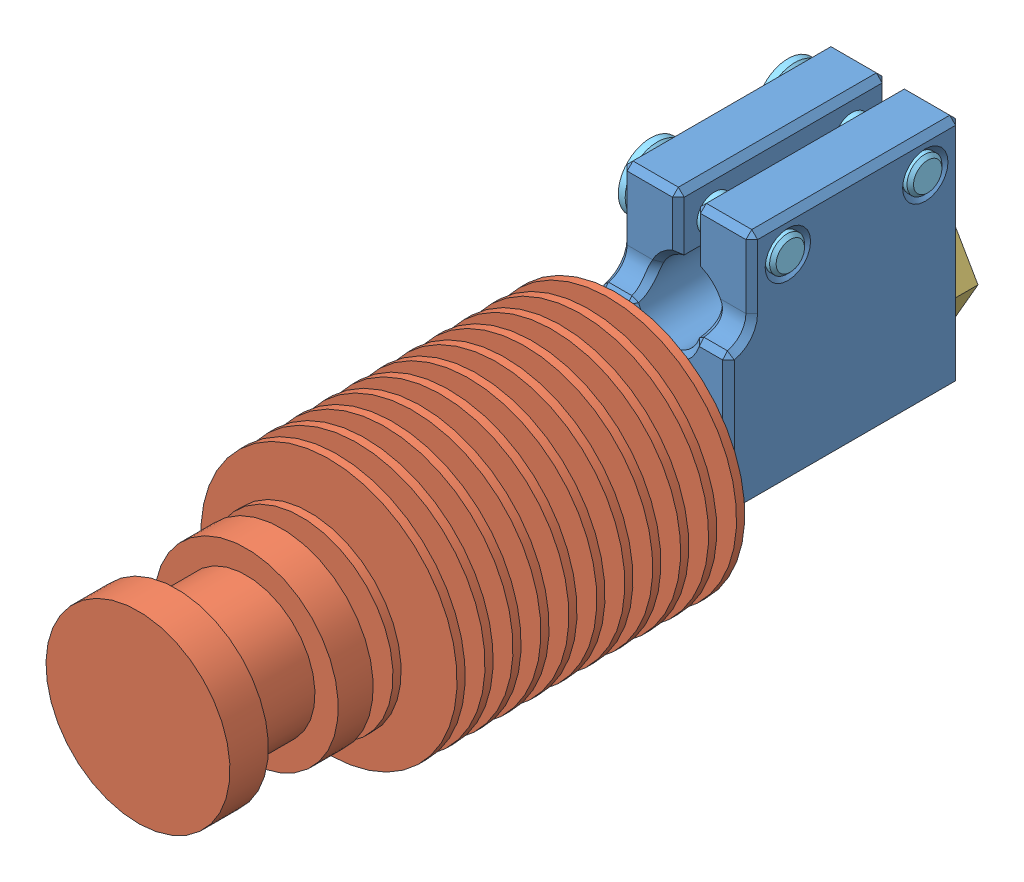
SolidWorks assembly Hotend Volcano J-head V6, configuration Valor predeterminado. Lengths in mm.
Overall size (26.65 29.04 70.3).
6 component instances, 5 part files, 19 mates.
Components (placement in the parent):
- Bloco Aquecedor-1: Bloco Aquecedor [Valor predeterminado] at origin size (11.2 20 20)
- Dissipador-1: Dissipador [Valor predeterminado] at (0.7469 3.7969 -4) x (0 0 -1) z (0.240623 -0.970619 0) size (41.1 22 22)
- Bico 0.4mm-1: Bico 0.4mm [Valor predeterminado] x (-1 0 0) z (0 0 -1) size (7.85 6.8 5.2)
- Tubo conector-1: Tubo conector [Valor predeterminado] at (0.7469 3.7969 24) x (-0.240623 0.970619 0) z (0 0 -1) size (6.8 6.8 4)
- socket countersunk head screw_iso-1: socket countersunk head screw_iso [ISO 10642 - M3 x 12 - 12N] at (-0.59 17.1 14.9) size (12 5.54 5.54)
- socket countersunk head screw_iso-2: socket countersunk head screw_iso [ISO 10642 - M3 x 12 - 12N] at (-0.59 17.1 3.1) x (1 0 0) z (0 0.924225 0.381849) size (12 5.54 5.54)
Mates (geometry in assembly coordinates):
- Coincidente1: coordinate: point of bloco aquecedor-1
- Concêntrico1: concentric aligned: cylinder of bloco aquecedor-1 through (5.6 5 20) axis (0 0 -1) radius 2.9; cylinder of Peça1^Hotend Volcano J-head V6-1 through (5.6 5 24) axis (0 0 -1) radius 11
- Distância1: distance = 4 mm anti-aligned: plane of bloco aquecedor-1 through (5.6 12.55 20) normal (0 0 1); plane of Peça1^Hotend Volcano J-head V6-1 through (5.6 5 24) normal (0 0 -1)
- No local2: in place: plane of Bloco Aquecedor-1 through (5.6 12.55 0) normal (0 0 -1); plane of Bico 0.4mm-1 through (0 0 0) normal (0 0 -1); moOrthogonalPlaneRef_w of Bloco Aquecedor-1 through (5.6 12.55 0) normal (0 0 -1); plane of Bico 0.4mm-1 through (0 0 0) normal (0 1 0); plane of Bloco Aquecedor-1 through (5.6 12.55 0) normal (0 0 -1); plane of Bico 0.4mm-1 through (0 0 0) normal (-1 0 0); plane of Bloco Aquecedor-1 through (5.6 12.55 0) normal (0 0 -1); unknown of Bico 0.4mm-1
- Coincidente5: coincident aligned: plane of ?; plane of ?
- Coincidente6: coincident aligned: moOrthogonalPlaneRef_w of bloco aquecedor-1 through (0 0 0) normal (0 1 0); plane of Peça2^Hotend Volcano J-head V6-1 through (0 0 0) normal (0 1 0)
- Coincidente7: coincident anti-aligned: moOrthogonalPlaneRef_w of bloco aquecedor-1 through (0 0 0) normal (1 0 0); plane of Peça2^Hotend Volcano J-head V6-1 through (0 0 0) normal (-1 0 0)
- No local3: in place: plane of Dissipador-1 through (5.6 5 24) normal (0 0 -1); plane of ? through (0 0 24) normal (0 0 -1); plane of Dissipador-1 through (5.6 5 24) normal (0 0 -1); plane of ? through (0 0 24) normal (0 1 0); plane of Dissipador-1 through (5.6 5 24) normal (0 0 -1); plane of ? through (0 0 24) normal (-1 0 0); plane of Dissipador-1 through (5.6 5 24) normal (0 0 -1); unknown of Tubo conector-1
- Coincidente8: coincident aligned: plane of ?; plane of ?
- Coincidente9: coincident aligned: moOrthogonalPlaneRef_w of Peça1^Hotend Volcano J-head V6-1 through (0.7469 3.7969 24) normal (0.970619 0.240623 0); plane of Peça3^Hotend Volcano J-head V6-1 through (0.7469 3.7969 24) normal (0.970619 0.240623 0)
- Coincidente10: coincident anti-aligned: moOrthogonalPlaneRef_w of Peça1^Hotend Volcano J-head V6-1 through (0.7469 3.7969 24) normal (0.240623 -0.970619 0); plane of Peça3^Hotend Volcano J-head V6-1 through (0.7469 3.7969 24) normal (-0.240623 0.970619 0)
- No local4: in place: plane of Dissipador-1 through (16.2768 7.6468 48.7) normal (0 0 1); plane of ? through (0 0 48.7) normal (0 0 1); plane of Dissipador-1 through (16.2768 7.6468 48.7) normal (0 0 1); plane of ? through (0 0 48.7) normal (0 1 0); plane of Dissipador-1 through (16.2768 7.6468 48.7) normal (0 0 1); plane of ? through (0 0 48.7) normal (1 0 0); plane of Dissipador-1 through (16.2768 7.6468 48.7) normal (0 0 1); unknown of ?
- Coincidente12: coincident aligned: plane of ?; plane of ?
- Coincidente13: coincident aligned: moOrthogonalPlaneRef_w of Peça1^Hotend Volcano J-head V6-1 through (0.7469 3.7969 48.7) normal (0.970619 0.240623 0); plane of Acoplador da ventoinha-1 through (0.7469 3.7969 48.7) normal (0.970619 0.240623 0)
- Coincidente14: coincident anti-aligned: moOrthogonalPlaneRef_w of Peça1^Hotend Volcano J-head V6-1 through (0.7469 3.7969 48.7) normal (-0.240623 0.970619 0); plane of Acoplador da ventoinha-1 through (0.7469 3.7969 48.7) normal (0.240623 -0.970619 0)
- Concêntrico6: concentric aligned: cylinder of bloco aquecedor-1 through (11.2 17.1 14.9) axis (1 0 0) radius 1.45; cone of socket countersunk head screw_iso-1 through (0 17.1 14.9) axis (1 0 0)
- Concêntrico7: concentric aligned: cylinder of bloco aquecedor-1 through (11.2 17.1 3.1) axis (1 0 0) radius 1.45; cone of socket countersunk head screw_iso-2 through (0 17.1 3.1) axis (1 0 0)
- Coincidente19: coincident aligned: plane of bloco aquecedor-1 through (0 0 20) normal (-1 0 0); circle of socket countersunk head screw_iso-2
- Coincidente20: coincident aligned: plane of bloco aquecedor-1 through (0 0 20) normal (-1 0 0); circle of socket countersunk head screw_iso-1
